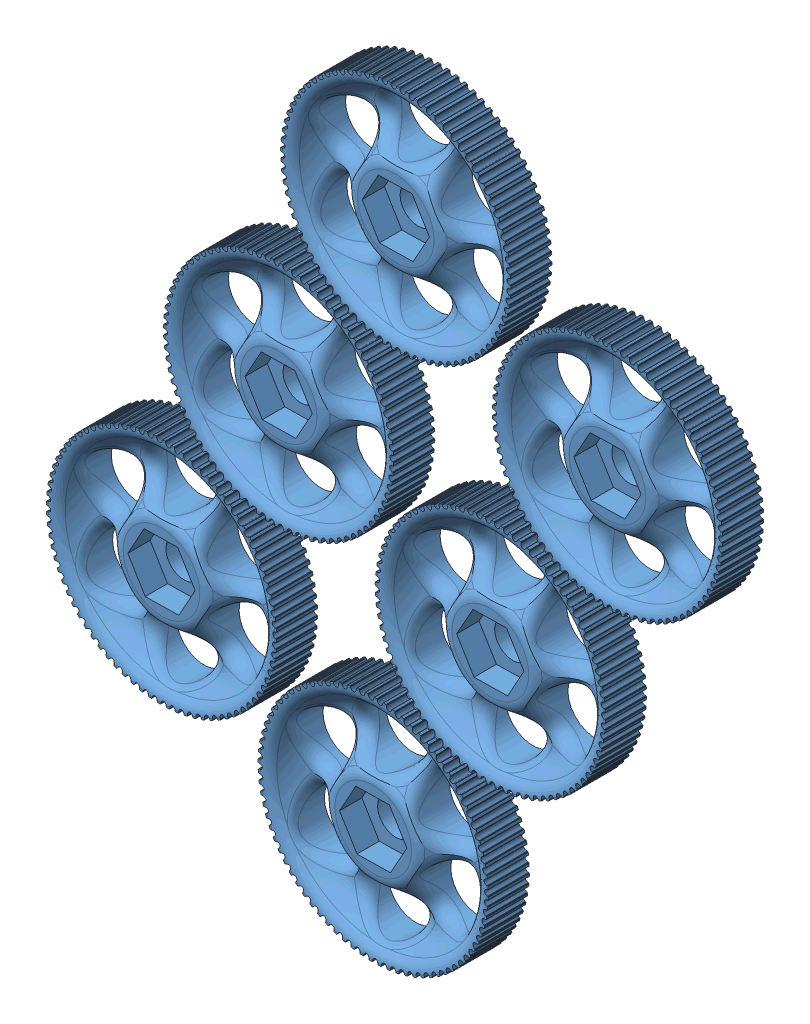
SolidWorks assembly Assem1, configuration Default. Lengths in mm.
Overall size (149 169.72 9.47).
6 component instances, 1 part files, 1 mates.
Components (placement in the parent):
- Parametric-Pulley-80-8-hex-1: Parametric-Pulley-80-8-hex [Default] at (-27.6448 3.0189 11) x (-0.999834 -0.018243 0) z (0 0 -1) size (50.4 50.4 9.47)
- Parametric-Pulley-80-8-hex-2: Parametric-Pulley-80-8-hex [Default] at (-74.02 28.6771 11) x (-0.999834 -0.018243 0) z (0 0 -1) size (50.4 50.4 9.47)
- Parametric-Pulley-80-8-hex-3: Parametric-Pulley-80-8-hex [Default] at (-53.303 -43.3562 11) x (-0.999834 -0.018243 0) z (0 0 -1) size (50.4 50.4 9.47)
- Parametric-Pulley-80-8-hex-4: Parametric-Pulley-80-8-hex [Default] at (-99.6782 -17.698 11) x (-0.999834 -0.018243 0) z (0 0 -1) size (50.4 50.4 9.47)
- Parametric-Pulley-80-8-hex-5: Parametric-Pulley-80-8-hex [Default] at (-78.9612 -89.7314 11) x (-0.999834 -0.018243 0) z (0 0 -1) size (50.4 50.4 9.47)
- Parametric-Pulley-80-8-hex-6: Parametric-Pulley-80-8-hex [Default] at (-125.3364 -64.0732 11) x (-0.999834 -0.018243 0) z (0 0 -1) size (50.4 50.4 9.47)
Mates (geometry in assembly coordinates):
- Coincident1: coincident anti-aligned: plane of Parametric-Pulley-80-8-hex-1 through (-27.6448 3.0189 0) normal (0 0 -1); plane of assembly
